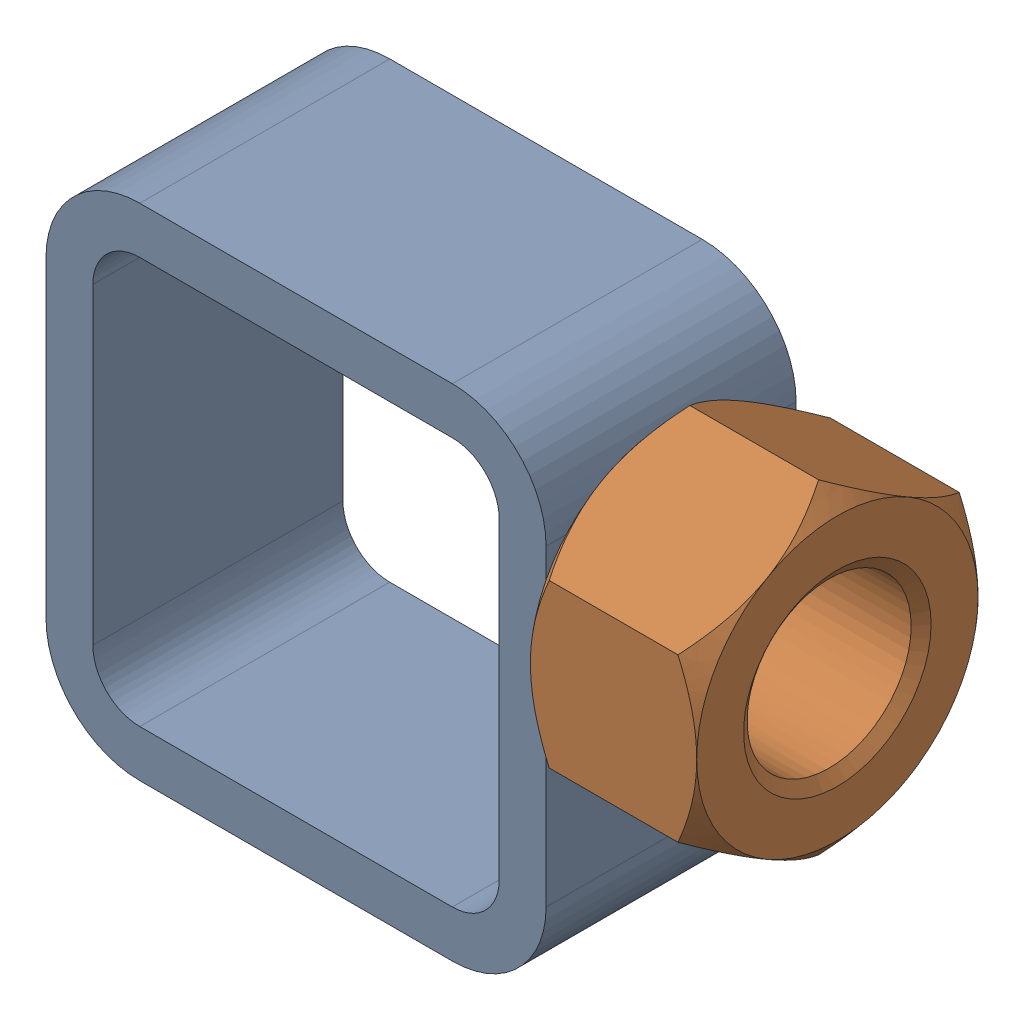
SolidWorks assembly 01-005-00-0-5, configuration Default. Lengths in mm.
Overall size (67.69 50.8 28.57).
2 component instances, 2 part files, 0 mates.
Components (placement in the parent):
- tube square_ai(PreviewCfg)-1: tube square_ai(PreviewCfg) [Default] at origin size (50.8 50.8 25.4)
- hex nut_ai(HNUT 0.7500-10-D-C)-1: hex nut_ai(HNUT 0.7500-10-D-C) [Default] at (67.691 31.75 0) x (0 0 -1) z (1 0 0) size (28.57 33 16.89)
